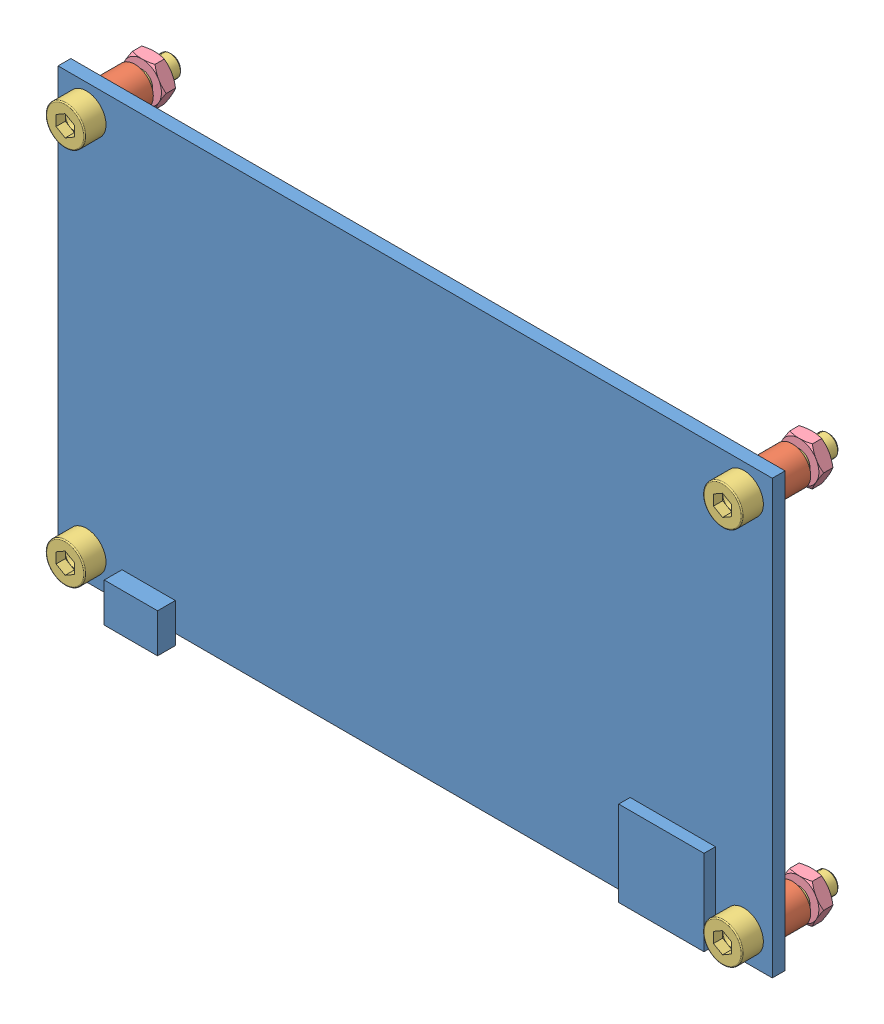
SolidWorks assembly Printrboard with screws2, configuration Default. Lengths in mm.
Overall size (100.5 62.73 15).
13 component instances, 4 part files, 12 mates.
Components (placement in the parent):
- Printrboard-1: Printrboard [Default] at origin size (100.5 62.4 4.3)
- Acrilyc 5mm washer-1: Acrilyc 5mm washer [Default] at (-377.25 58.55 -5) x (0 -1 0) z (0 0 1) size (5.2 5.2 5)
- Acrilyc 5mm washer-2: Acrilyc 5mm washer [Default] at (-377.25 5.25 -5) x (0 -1 0) z (0 0 1) size (5.2 5.2 5)
- Acrilyc 5mm washer-3: Acrilyc 5mm washer [Default] at (377.25 2.35 -5) x (0 1 0) z (0 0 1) size (5.2 5.2 5)
- Acrilyc 5mm washer-4: Acrilyc 5mm washer [Default] at (377.25 55.65 -5) x (0 1 0) z (0 0 1) size (5.2 5.2 5)
- ISO 4762 M3 x 10 --- 10N-1: ISO 4762 M3 x 10 --- 10N [ISO 4762 M3 x 12 --- 12N] at (-46.25 3.8 4.8) x (0 0 -1) z (-1 0 0) size (15 5.5 5.5)
- ISO 4762 M3 x 10 --- 10N-2: ISO 4762 M3 x 10 --- 10N [ISO 4762 M3 x 12 --- 12N] at (-46.25 57.1 4.8) x (0 0 -1) z (-1 0 0) size (15 5.5 5.5)
- ISO 4762 M3 x 10 --- 10N-3: ISO 4762 M3 x 10 --- 10N [ISO 4762 M3 x 12 --- 12N] at (46.25 57.1 4.8) x (0 0 -1) z (-1 0 0) size (15 5.5 5.5)
- ISO 4762 M3 x 10 --- 10N-4: ISO 4762 M3 x 10 --- 10N [ISO 4762 M3 x 12 --- 12N] at (46.25 3.8 4.8) x (0 0 -1) z (-1 0 0) size (15 5.5 5.5)
- hex thin nut chamfered gradeab_iso-1: hex thin nut chamfered gradeab_iso [Hexagon Thin Nut ISO - 4035 - M3 - N] at (-46.25 3.8 -7.8) x (0 1 0) z (0 0 -1) size (5.5 6.35 1.8)
- hex thin nut chamfered gradeab_iso-2: hex thin nut chamfered gradeab_iso [Hexagon Thin Nut ISO - 4035 - M3 - N] at (46.25 3.8 -6) x (-0.866025 -0.5 0) z (0 0 1) size (5.5 6.35 1.8)
- hex thin nut chamfered gradeab_iso-3: hex thin nut chamfered gradeab_iso [Hexagon Thin Nut ISO - 4035 - M3 - N] at (-46.25 57.1 -6) x (-0.866025 -0.5 0) z (0 0 1) size (5.5 6.35 1.8)
- hex thin nut chamfered gradeab_iso-4: hex thin nut chamfered gradeab_iso [Hexagon Thin Nut ISO - 4035 - M3 - N] at (46.25 57.1 -6) x (0 -1 0) z (0 0 1) size (5.5 6.35 1.8)
Mates (geometry in assembly coordinates):
- Concentric40052: concentric aligned: cylinder of Printrboard-1 through (-46.25 3.8 -0.001) axis (0 0 1) radius 1.75; cylinder of ISO 4762 M3 x 10 --- 10N-1 through (-46.25 3.8 36.55) axis (0 0 1) radius 2.75
- Coincident787159: coincident anti-aligned: plane of Printrboard-1 through (-50.25 0 1.8) normal (0 0 1); plane of ISO 4762 M3 x 10 --- 10N-1 through (-46.25 1.05 1.8) normal (0 0 -1)
- Concentric40053: concentric aligned: cylinder of Printrboard-1 through (-46.25 57.1 -0.001) axis (0 0 1) radius 1.75; cylinder of ISO 4762 M3 x 10 --- 10N-2 through (-46.25 57.1 36.55) axis (0 0 1) radius 2.75
- Coincident787160: coincident anti-aligned: plane of Printrboard-1 through (-50.25 0 1.8) normal (0 0 1); plane of ISO 4762 M3 x 10 --- 10N-2 through (-46.25 54.35 1.8) normal (0 0 -1)
- Concentric40054: concentric aligned: cylinder of Printrboard-1 through (46.25 57.1 -0.001) axis (0 0 1) radius 1.75; cylinder of ISO 4762 M3 x 10 --- 10N-3 through (46.25 57.1 36.55) axis (0 0 1) radius 2.75
- Coincident787161: coincident anti-aligned: plane of Printrboard-1 through (-50.25 0 1.8) normal (0 0 1); plane of ISO 4762 M3 x 10 --- 10N-3 through (46.25 54.35 1.8) normal (0 0 -1)
- Concentric40055: concentric aligned: cylinder of Printrboard-1 through (46.25 3.8 -0.001) axis (0 0 1) radius 1.75; cylinder of ISO 4762 M3 x 10 --- 10N-4 through (46.25 3.8 36.55) axis (0 0 1) radius 2.75
- Coincident787162: coincident anti-aligned: plane of Printrboard-1 through (-50.25 0 1.8) normal (0 0 1); plane of ISO 4762 M3 x 10 --- 10N-4 through (46.25 1.05 1.8) normal (0 0 -1)
- Concentric401122: concentric anti-aligned: cylinder of ISO 4762 M3 x 10 --- 10N-1 through (-46.25 3.8 36.55) axis (0 0 1) radius 1.5; cylinder of hex thin nut chamfered gradeab_iso-1 through (-46.25 3.8 -6) axis (0 0 -1) radius 1.25
- Concentric401119: concentric aligned: cylinder of ISO 4762 M3 x 10 --- 10N-4 through (46.25 3.8 36.55) axis (0 0 1) radius 1.5; cylinder of hex thin nut chamfered gradeab_iso-2 through (46.25 3.8 -31.0375) axis (0 0 1) radius 1.5
- Concentric401120: concentric aligned: cylinder of ISO 4762 M3 x 10 --- 10N-2 through (-46.25 57.1 36.55) axis (0 0 1) radius 1.5; cylinder of hex thin nut chamfered gradeab_iso-3 through (-46.25 57.1 -31.0375) axis (0 0 1) radius 1.5
- Concentric401121: concentric aligned: cylinder of ISO 4762 M3 x 10 --- 10N-3 through (46.25 57.1 36.55) axis (0 0 1) radius 1.5; cylinder of hex thin nut chamfered gradeab_iso-4 through (46.25 57.1 -31.0375) axis (0 0 1) radius 1.5
